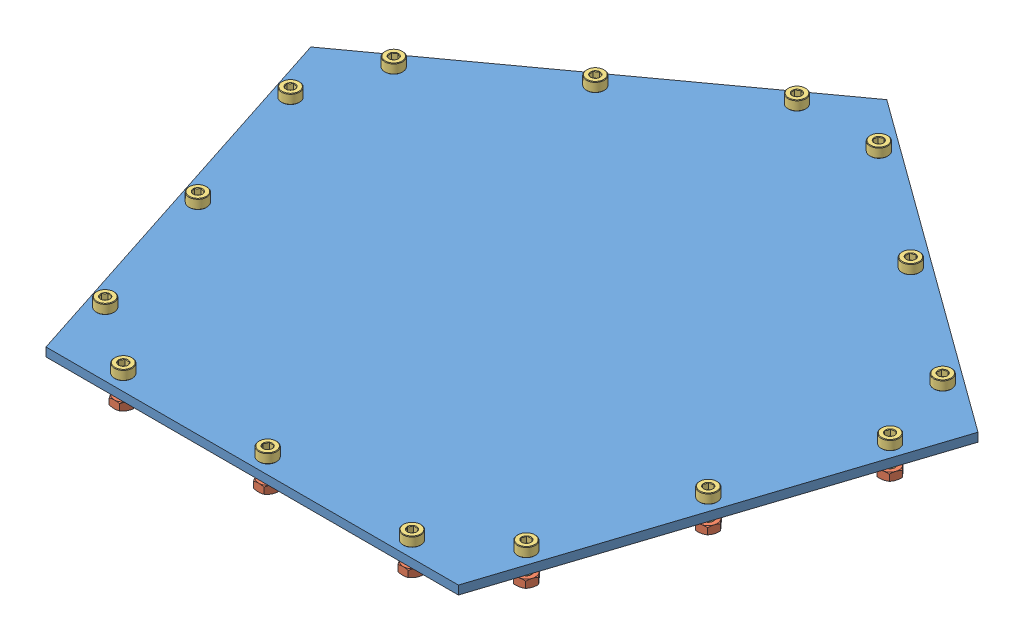
SolidWorks assembly Assem3, configuration Default. Lengths in mm.
Overall size (205.49 11.35 195.43).
46 component instances, 3 part files, 9 mates.
Components (placement in the parent):
- Acrylic Sid Plate-1: Acrylic Sid Plate [Default] at origin size (205.49 2.67 195.43)
- Assem4^Assem3-1: Assem4^Assem3 [Default] at (-44.45 -5.4665 82.6378) x (0 0 1) z (-1 0 0) size (5.5 11.35 6.35) (virtual)
  - 90592A085_STEEL HEX NUT-1: 90592A085_STEEL HEX NUT [90592A085] at origin size (5.5 2.79 6.35)
  - 91502A103_BLUE ALLOY STEEL SOCKET HEAD CAP SCREW-1: 91502A103_BLUE ALLOY STEEL SOCKET HEAD CAP SCREW [91502A103] at (0 -1.2 0) x (-1 0 0) z (0 -1 0) size (5.5 5.5 11.2)
- Assem4^Assem3-2: Assem4^Assem3 [Default] at (0 -5.4665 82.6378) x (0.866025 0 -0.5) z (0.5 0 0.866025) size (5.5 11.35 6.35) (virtual)
  - 90592A085_STEEL HEX NUT-1: 90592A085_STEEL HEX NUT [90592A085] at origin size (5.5 2.79 6.35)
  - 91502A103_BLUE ALLOY STEEL SOCKET HEAD CAP SCREW-1: 91502A103_BLUE ALLOY STEEL SOCKET HEAD CAP SCREW [91502A103] at (0 -1.2 0) x (-1 0 0) z (0 -1 0) size (5.5 5.5 11.2)
- Assem4^Assem3-3: Assem4^Assem3 [Default] at (44.45 -5.4665 82.6378) x (0.866025 0 -0.5) z (0.5 0 0.866025) size (5.5 11.35 6.35) (virtual)
  - 90592A085_STEEL HEX NUT-1: 90592A085_STEEL HEX NUT [90592A085] at origin size (5.5 2.79 6.35)
  - 91502A103_BLUE ALLOY STEEL SOCKET HEAD CAP SCREW-1: 91502A103_BLUE ALLOY STEEL SOCKET HEAD CAP SCREW [91502A103] at (0 -1.2 0) x (-1 0 0) z (0 -1 0) size (5.5 5.5 11.2)
- Assem4^Assem3-4: Assem4^Assem3 [Default] at (-64.8574 -5.4665 67.8109) x (0.743145 0 0.669131) z (-0.669131 0 0.743145) size (5.5 11.35 6.35) (virtual)
  - 90592A085_STEEL HEX NUT-1: 90592A085_STEEL HEX NUT [90592A085] at origin size (5.5 2.79 6.35)
  - 91502A103_BLUE ALLOY STEEL SOCKET HEAD CAP SCREW-1: 91502A103_BLUE ALLOY STEEL SOCKET HEAD CAP SCREW [91502A103] at (0 -1.2 0) x (-1 0 0) z (0 -1 0) size (5.5 5.5 11.2)
- Assem4^Assem3-5: Assem4^Assem3 [Default] at (-84.5341 -5.4665 -40.7283) x (-0.406737 0 0.913545) z (-0.913545 0 -0.406737) size (5.5 11.35 6.35) (virtual)
  - 90592A085_STEEL HEX NUT-1: 90592A085_STEEL HEX NUT [90592A085] at origin size (5.5 2.79 6.35)
  - 91502A103_BLUE ALLOY STEEL SOCKET HEAD CAP SCREW-1: 91502A103_BLUE ALLOY STEEL SOCKET HEAD CAP SCREW [91502A103] at (0 -1.2 0) x (-1 0 0) z (0 -1 0) size (5.5 5.5 11.2)
- Assem4^Assem3-6: Assem4^Assem3 [Default] at (12.6124 -5.4665 -92.9824) x (-0.994522 0 -0.104528) z (0.104528 0 -0.994522) size (5.5 11.35 6.35) (virtual)
  - 90592A085_STEEL HEX NUT-1: 90592A085_STEEL HEX NUT [90592A085] at origin size (5.5 2.79 6.35)
  - 91502A103_BLUE ALLOY STEEL SOCKET HEAD CAP SCREW-1: 91502A103_BLUE ALLOY STEEL SOCKET HEAD CAP SCREW [91502A103] at (0 -1.2 0) x (-1 0 0) z (0 -1 0) size (5.5 5.5 11.2)
- Assem4^Assem3-7: Assem4^Assem3 [Default] at (92.329 -5.4665 -16.738) x (-0.207912 0 -0.978148) z (0.978148 0 -0.207912) size (5.5 11.35 6.35) (virtual)
  - 90592A085_STEEL HEX NUT-1: 90592A085_STEEL HEX NUT [90592A085] at origin size (5.5 2.79 6.35)
  - 91502A103_BLUE ALLOY STEEL SOCKET HEAD CAP SCREW-1: 91502A103_BLUE ALLOY STEEL SOCKET HEAD CAP SCREW [91502A103] at (0 -1.2 0) x (-1 0 0) z (0 -1 0) size (5.5 5.5 11.2)
- Assem4^Assem3-8: Assem4^Assem3 [Default] at (-78.5932 -5.4665 25.5365) x (0.743145 0 0.669131) z (-0.669131 0 0.743145) size (5.5 11.35 6.35) (virtual)
  - 90592A085_STEEL HEX NUT-1: 90592A085_STEEL HEX NUT [90592A085] at origin size (5.5 2.79 6.35)
  - 91502A103_BLUE ALLOY STEEL SOCKET HEAD CAP SCREW-1: 91502A103_BLUE ALLOY STEEL SOCKET HEAD CAP SCREW [91502A103] at (0 -1.2 0) x (-1 0 0) z (0 -1 0) size (5.5 5.5 11.2)
- Assem4^Assem3-9: Assem4^Assem3 [Default] at (-48.5733 -5.4665 -66.8553) x (-0.406737 0 0.913545) z (-0.913545 0 -0.406737) size (5.5 11.35 6.35) (virtual)
  - 90592A085_STEEL HEX NUT-1: 90592A085_STEEL HEX NUT [90592A085] at origin size (5.5 2.79 6.35)
  - 91502A103_BLUE ALLOY STEEL SOCKET HEAD CAP SCREW-1: 91502A103_BLUE ALLOY STEEL SOCKET HEAD CAP SCREW [91502A103] at (0 -1.2 0) x (-1 0 0) z (0 -1 0) size (5.5 5.5 11.2)
- Assem4^Assem3-10: Assem4^Assem3 [Default] at (48.5733 -5.4665 -66.8553) x (-0.994522 0 -0.104528) z (0.104528 0 -0.994522) size (5.5 11.35 6.35) (virtual)
  - 90592A085_STEEL HEX NUT-1: 90592A085_STEEL HEX NUT [90592A085] at origin size (5.5 2.79 6.35)
  - 91502A103_BLUE ALLOY STEEL SOCKET HEAD CAP SCREW-1: 91502A103_BLUE ALLOY STEEL SOCKET HEAD CAP SCREW [91502A103] at (0 -1.2 0) x (-1 0 0) z (0 -1 0) size (5.5 5.5 11.2)
- Assem4^Assem3-11: Assem4^Assem3 [Default] at (78.5932 -5.4665 25.5365) x (-0.207912 0 -0.978148) z (0.978148 0 -0.207912) size (5.5 11.35 6.35) (virtual)
  - 90592A085_STEEL HEX NUT-1: 90592A085_STEEL HEX NUT [90592A085] at origin size (5.5 2.79 6.35)
  - 91502A103_BLUE ALLOY STEEL SOCKET HEAD CAP SCREW-1: 91502A103_BLUE ALLOY STEEL SOCKET HEAD CAP SCREW [91502A103] at (0 -1.2 0) x (-1 0 0) z (0 -1 0) size (5.5 5.5 11.2)
- Assem4^Assem3-12: Assem4^Assem3 [Default] at (-92.329 -5.4665 -16.738) x (-0.951057 0 0.309017) z (-0.309017 0 -0.951057) size (5.5 11.35 6.35) (virtual)
  - 90592A085_STEEL HEX NUT-1: 90592A085_STEEL HEX NUT [90592A085] at origin size (5.5 2.79 6.35)
  - 91502A103_BLUE ALLOY STEEL SOCKET HEAD CAP SCREW-1: 91502A103_BLUE ALLOY STEEL SOCKET HEAD CAP SCREW [91502A103] at (0 -1.2 0) x (-1 0 0) z (0 -1 0) size (5.5 5.5 11.2)
- Assem4^Assem3-13: Assem4^Assem3 [Default] at (-12.6124 -5.4665 -92.9824) x (-0.587785 0 -0.809017) z (0.809017 0 -0.587785) size (5.5 11.35 6.35) (virtual)
  - 90592A085_STEEL HEX NUT-1: 90592A085_STEEL HEX NUT [90592A085] at origin size (5.5 2.79 6.35)
  - 91502A103_BLUE ALLOY STEEL SOCKET HEAD CAP SCREW-1: 91502A103_BLUE ALLOY STEEL SOCKET HEAD CAP SCREW [91502A103] at (0 -1.2 0) x (-1 0 0) z (0 -1 0) size (5.5 5.5 11.2)
- Assem4^Assem3-14: Assem4^Assem3 [Default] at (84.5341 -5.4665 -40.7283) x (0.587785 0 -0.809017) z (0.809017 0 0.587785) size (5.5 11.35 6.35) (virtual)
  - 90592A085_STEEL HEX NUT-1: 90592A085_STEEL HEX NUT [90592A085] at origin size (5.5 2.79 6.35)
  - 91502A103_BLUE ALLOY STEEL SOCKET HEAD CAP SCREW-1: 91502A103_BLUE ALLOY STEEL SOCKET HEAD CAP SCREW [91502A103] at (0 -1.2 0) x (-1 0 0) z (0 -1 0) size (5.5 5.5 11.2)
- Assem4^Assem3-15: Assem4^Assem3 [Default] at (64.8574 -5.4665 67.8109) x (0.951057 0 0.309017) z (-0.309017 0 0.951057) size (5.5 11.35 6.35) (virtual)
  - 90592A085_STEEL HEX NUT-1: 90592A085_STEEL HEX NUT [90592A085] at origin size (5.5 2.79 6.35)
  - 91502A103_BLUE ALLOY STEEL SOCKET HEAD CAP SCREW-1: 91502A103_BLUE ALLOY STEEL SOCKET HEAD CAP SCREW [91502A103] at (0 -1.2 0) x (-1 0 0) z (0 -1 0) size (5.5 5.5 11.2)
Mates (geometry in assembly coordinates):
- Coincident6: coincident anti-aligned: plane of Acrylic Sid Plate-1 through (0 1.3335 0) normal (0 1 0); plane of Assem4^Assem3-1/91502A103_BLUE ALLOY STEEL SOCKET HEAD CAP SCREW-1 through (-44.45 1.3335 82.6378) normal (0 -1 0)
- Concentric3: concentric aligned: cylinder of Acrylic Sid Plate-1 through (-44.45 1.3335 82.6378) axis (0 -1 0) radius 1.7145; cylinder of Assem4^Assem3-1/91502A103_BLUE ALLOY STEEL SOCKET HEAD CAP SCREW-1 through (-44.45 4.3335 82.6378) axis (0 -1 0) radius 2.75
- Parallel5: parallel anti-aligned: plane of Acrylic Sid Plate-1 through (63.5 1.3335 87.4003) normal (0 0 1); plane of Assem4^Assem3-1/91502A103_BLUE ALLOY STEEL SOCKET HEAD CAP SCREW-1 through (-44.45 -6.6665 82.6378) normal (0 0 -1)
- Coincident7: coincident anti-aligned: plane of Acrylic Sid Plate-1 through (0 1.3335 0) normal (0 1 0); plane of Assem4^Assem3-2/91502A103_BLUE ALLOY STEEL SOCKET HEAD CAP SCREW-1 through (0 1.3335 82.6378) normal (0 -1 0)
- Coincident8: coincident anti-aligned: plane of Acrylic Sid Plate-1 through (0 1.3335 0) normal (0 1 0); plane of Assem4^Assem3-3/91502A103_BLUE ALLOY STEEL SOCKET HEAD CAP SCREW-1 through (44.45 1.3335 82.6378) normal (0 -1 0)
- Concentric4: concentric aligned: cylinder of Acrylic Sid Plate-1 through (0 1.3335 82.6378) axis (0 -1 0) radius 1.7145; cylinder of Assem4^Assem3-2/91502A103_BLUE ALLOY STEEL SOCKET HEAD CAP SCREW-1 through (0 4.3335 82.6378) axis (0 -1 0) radius 2.75
- Concentric5: concentric aligned: cylinder of Acrylic Sid Plate-1 through (44.45 1.3335 82.6378) axis (0 -1 0) radius 1.7145; cylinder of Assem4^Assem3-3/91502A103_BLUE ALLOY STEEL SOCKET HEAD CAP SCREW-1 through (44.45 4.3335 82.6378) axis (0 -1 0) radius 2.75
- Coincident9: coincident aligned: plane of Assem4^Assem3-1/90592A085_STEEL HEX NUT-1 through (-46.0377 -4.2665 85.3878) normal (0 0 1); plane of Assem4^Assem3-2/90592A085_STEEL HEX NUT-1 through (-1.5877 -4.2665 85.3878) normal (0 0 1)
- Coincident10: coincident aligned: plane of Assem4^Assem3-1/90592A085_STEEL HEX NUT-1 through (-46.0377 -4.2665 85.3878) normal (0 0 1); plane of Assem4^Assem3-3/90592A085_STEEL HEX NUT-1 through (42.8623 -4.2665 85.3878) normal (0 0 1)
